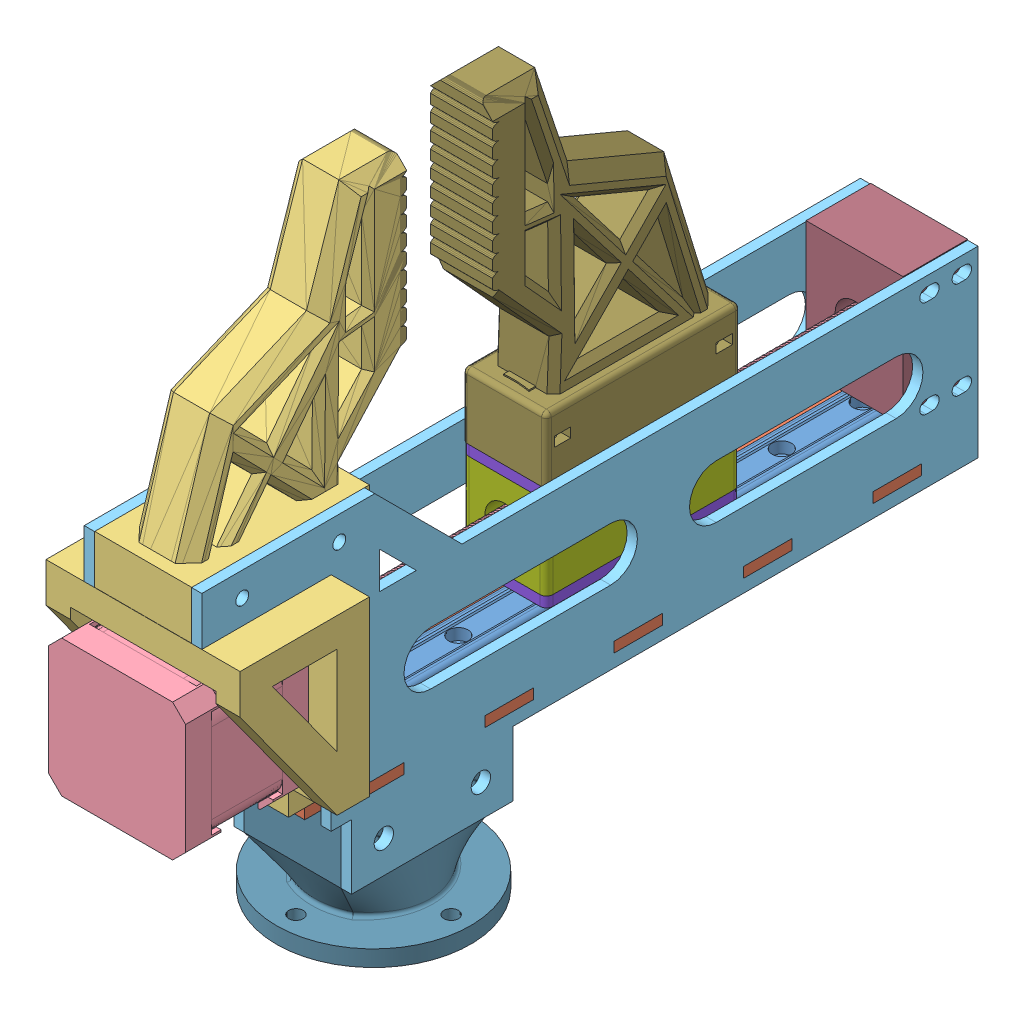
SolidWorks assembly UOM20-4A002, configuration Default. Lengths in mm.
Overall size (60 201.12 248).
17 component instances, 14 part files, 31 mates.
Components (placement in the parent):
- XXUOM20-4P006-1: XXUOM20-4P006 [Default] at origin size (13.08 8.01 200)
- XXUOM20-4P007-1: XXUOM20-4P007 [Default] at (-24.2561 0 -84.2912) x (1 0 0) z (0 1 0) size (36.35 200 3.17)
- XXUOM20-4P008-1: XXUOM20-4P008 [Default] at (30 8.03 40) x (-1 0 0) z (0 0 -1) size (60 153.95 71.54)
- Stepper with LeadScrew-1: Stepper with LeadScrew [Default] at (0 29.78 18) x (1 0 0) z (0 1 0) size (42.3 239.5 42.3)
- XXUOM20-4P009-1: XXUOM20-4P009 [Default] at (18.175 145.03 -15) x (0 0 -1) z (1 0 0) size (240 103.7 3.17)
- XXUOM20-4P009-2: XXUOM20-4P009 [Default] at (-15 145.03 -15) x (0 0 -1) z (1 0 0) size (240 103.7 3.17)
- 7917N13_HIGH-CYCLE LOW-PROFILE BALL BEARING CARRIAGE-1: 7917N13_HIGH-CYCLE LOW-PROFILE BALL BEARING CARRIAGE [7917N13] at (0.4 7.1 -102.0336) size (27 11 34.4)
- UOM20-4P010-1: UOM20-4P010 [Default] at (6.5573 38.7283 -72.0092) x (0 0 1) z (0 -1 0) size (60 26 32.35)
  - Block1-1: Block1 [Default] at (-59.7244 -6.4427 -4.0467) size (60 26 26)
  - spring plate-1: spring plate [Default] at (-59.7244 -6.4427 -4.0467) x (-1 0 0) z (0 0 -1) size (60 26 3.17)
  - spring plate-2: spring plate [Default] at (0.2756 -6.4427 21.9533) size (60 26 3.17)
  - leadnut-1: leadnut [Default] at (-36.9744 6.5573 8.9533) x (-1 0 0) z (0 -1 0) size (10 24 10.5)
  - 9434K135_MUSIC-WIRE STEEL COMPRESSION SPRINGS-1: 9434K135_MUSIC-WIRE STEEL COMPRESSION SPRINGS [9434K135] at (-41.4744 6.4644 9.0297) x (0 -1 0) z (0 0 1) size (15.72 32.66 15.84)
  - guide block-1: guide block [Default] at (-41.4744 -1.4427 21.9533) x (0 1 0) z (-1 0 0) size (16 26 7)
- XXUOM20-4P011-1: XXUOM20-4P011 [Default] at (-85.0656 -1.6348 38.7958) x (1 0 0) z (0 1 0) size (26 73.24 107.42)
- XXUOM20-4P012-1: XXUOM20-4P012 [Default] at (-15 9.78 -200) size (30 40 20)
- XXUOM20-4P013-1: XXUOM20-4P013 [Default] at (0 -42.175 -31.2815) x (0 0 1) z (0 1 0) size (60 60 40)
Mates (geometry in assembly coordinates):
- Coincident1: coincident anti-aligned: plane of Em4HMIiUfR_CADModel_0-1 through (-5.8438 0 -200) normal (0 -1 0); plane of UOM20-4P007-1 through (-24.2561 0 -84.2912) normal (0 1 0)
- Coincident2: coincident aligned: circle of Em4HMIiUfR_CADModel_0-1; cylinder of UOM20-4P007-1 through (0 -3.175 -32.5) axis (0 1 0) radius 1.75
- Concentric2: concentric aligned: circle of Em4HMIiUfR_CADModel_0-1; circle of Part1-1
- Concentric3: concentric aligned: circle of Part4-1; circle of Stepper with LeadScrew-1
- Coincident3: coincident anti-aligned: plane of UOM20-4P008-1 through (30 8.03 10) normal (0 0 1); plane of Stepper with LeadScrew-1 through (0 29.78 10) normal (0 0 -1)
- Parallel1: parallel aligned: plane of UOM20-4P008-1 through (-30 48.03 0) normal (-1 0 0); plane of Stepper with LeadScrew-1 through (-21.1 44.68 40) normal (-1 0 0)
- Distance1: distance = 5 mm anti-aligned: plane of UOM20-4P007-1 through (-18.175 -3.175 5) normal (0 0 1); plane of UOM20-4P008-1 through (30 8.03 0) normal (0 0 -1)
- Parallel2: parallel anti-aligned: plane of UOM20-4P007-1 through (-24.2561 -3.175 -84.2912) normal (0 -1 0); plane of UOM20-4P008-1 through (-15 76.53 39.9268) normal (0 1 0)
- Coincident7: coincident aligned: plane of UOM20-4P007-1 through (-15 -10 17.5) normal (-1 0 0); plane of UOM20-4P008-1 through (-15 8.03 40) normal (-1 0 0)
- Coincident8: coincident anti-aligned: plane of UOM20-4P007-1 through (18.175 -10 -7.5) normal (0 0 1); plane of Part2-1 through (15 -3.175 -7.5) normal (0 0 -1)
- Coincident9: coincident anti-aligned: plane of UOM20-4P007-1 through (15 -10 17.5) normal (1 0 0); plane of Part2-1 through (15 145.03 -15) normal (-1 0 0)
- Coincident10: coincident anti-aligned: plane of UOM20-4P007-1 through (-24.2561 0 -84.2912) normal (0 1 0); plane of Part2-1 through (15 0 -102.5) normal (0 -1 0)
- Distance2: distance = 13 mm aligned: plane of 7917N13_HIGH-CYCLE LOW-PROFILE BALL BEARING CARRIAGE-1 through (-12 13 -112.3336) normal (0 1 0); plane of UOM20-4P007-1 through (-24.2561 0 -84.2912) normal (0 1 0)
- Coincident14: coincident anti-aligned: plane of 7917N13_HIGH-CYCLE LOW-PROFILE BALL BEARING CARRIAGE-1 through (-12.69 13.6 -84.8336) normal (0 1 0); plane of spring mech-1/spring plate-2 through (13 13.6 -71.7336) normal (0 -1 0)
- Coincident15: coincident aligned: plane of 7917N13_HIGH-CYCLE LOW-PROFILE BALL BEARING CARRIAGE-1 through (-13 12 -91.7336) normal (-1 0 0); plane of spring mech-1/Block1-1 through (-13 16.775 -129.7336) normal (-1 0 0)
- Distance3: distance = 12.5 mm aligned: plane of 7917N13_HIGH-CYCLE LOW-PROFILE BALL BEARING CARRIAGE-1 through (-5.45 6.9821 -119.2336) normal (0 0 -1); plane of spring mech-1/Block1-1 through (11 16.775 -131.7336) normal (0 0 -1)
- Coincident17: coincident anti-aligned: plane of spring mech-1/spring plate-1 through (13 45.95 -131.7336) normal (0 1 0); plane of pincher-1 through (-85.0656 45.95 38.7958) normal (0 -1 0)
- Coincident18: coincident aligned: plane of spring mech-1/Block1-1 through (11 16.775 -71.7336) normal (0 0 1); plane of pincher-1 through (13 45.95 -71.7336) normal (0 0 1)
- Coincident19: coincident anti-aligned: plane of UOM20-4P008-1 through (-30 61.53 0) normal (0 1 0); plane of Part2-1 through (15 61.53 40) normal (0 -1 0)
- Distance4: distance = 2 mm anti-aligned: plane of spring mech-1/Block1-1 through (13 16.775 -129.7336) normal (1 0 0); plane of Part2-1 through (15 145.03 -15) normal (-1 0 0)
- Coincident21: coincident aligned: plane of spring mech-1/Block1-1 through (-13 16.775 -129.7336) normal (-1 0 0); plane of pincher-1 through (-13 45.95 -131.7336) normal (-1 0 0)
- Coincident23: coincident anti-aligned: plane of spring mech-1/spring plate-1 through (13 45.95 -131.7336) normal (0 1 0); plane of pincher-1 through (-85.0656 45.95 38.7958) normal (0 -1 0)
- Coincident24: coincident anti-aligned: plane of UOM20-4P008-1 through (-15 8.03 40) normal (-1 0 0); plane of Part2-2 through (-15 145.03 -15) normal (1 0 0)
- Coincident25: coincident aligned: plane of Part2-1 through (15 49.53 -200) normal (0 0 -1); plane of Part2-2 through (-18.175 49.53 -200) normal (0 0 -1)
- Concentric4: concentric anti-aligned: circle of Part4-1; cylinder of Part3-1 through (0 29.78 -192) axis (0 0 1) radius 6
- Coincident27: coincident aligned: plane of Part2-2 through (-18.175 49.53 -200) normal (0 0 -1); plane of Part3-1 through (-15 9.78 -200) normal (0 0 -1)
- Coincident28: coincident anti-aligned: plane of Part2-2 through (-15 145.03 -15) normal (1 0 0); plane of UOM20-4P013-1 through (-15 -7.175 -56.2815) normal (-1 0 0)
- Coincident33: coincident aligned: line of UOM20-4P007-1 through (-18.175 0 -182.5) axis (0 0 1); line of Part2-2 through (-18.175 0 -182.5) axis (0 0 1)
- Width1: width anti-aligned: plane of UOM20-4P013-1 through (15 -7.175 -56.2815) normal (1 0 0); plane of Part2-1 through (-15 -7.175 -56.2815) normal (-1 0 0); plane of UOM20-4P013-1 through (15 145.03 -15) normal (-1 0 0); plane of Part2-2 through (-15 145.03 -15) normal (1 0 0)
- Width2: width anti-aligned: plane of UOM20-4P013-1 through (-15 -7.175 -56.2815) normal (0 0 -1); plane of Part2-1 through (-15 -7.175 -6.2815) normal (0 0 1); plane of UOM20-4P013-1 through (15 -7.175 -6.2815) normal (0 0 1); plane of Part2-1 through (15 -7.175 -56.2815) normal (0 0 -1)
- Coincident34: coincident aligned: line of Part2-1 through (15 -27.175 -6.2815) axis (0 0 -1); line of UOM20-4P013-1 through (15 -27.175 -6.2815) axis (0 0 -1)
